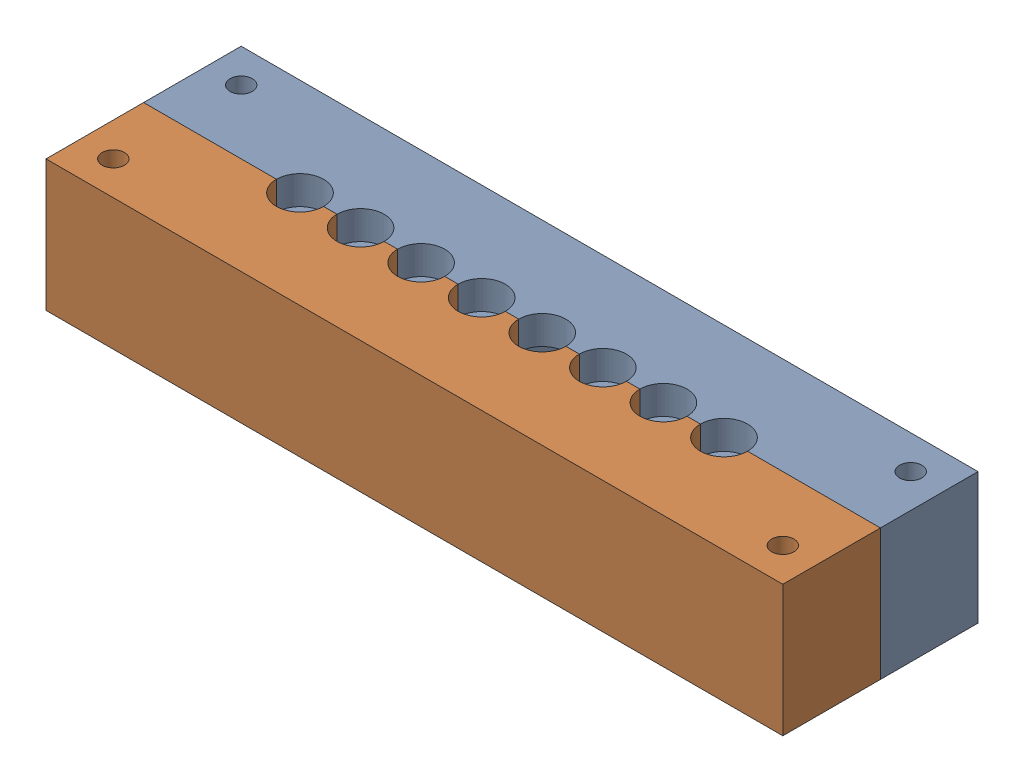
SolidWorks assembly board and upper, configuration Default. Lengths in mm.
Overall size (109.48 20.46 29).
15 component instances, 4 part files, 3 mates.
Components (placement in the parent):
- Photodiode_upper_v3-1: Photodiode_upper_v3 [Default] at (68.222 41.734 71.6201) size (109.48 19.5 29)
- Photodiode_Board-3: Photodiode_Board [Default] at (-11.918 65.909 111.5201) x (1 0 0) z (0 1 0) size (109.48 29 0)
  - Photodiode_Board_BOARD-1: Photodiode_Board_BOARD [Default] at origin (suppressed, hidden)
  - FP-PEC06SBBN-MFG_CMP-25680-000045-1-1: FP-PEC06SBBN-MFG_CMP-25680-000045-1 [Default] at (46.02 26.67 0.4115) (suppressed, hidden)
  - FP-PEC06SBBN-MFG_CMP-25680-000045-1-2: FP-PEC06SBBN-MFG_CMP-25680-000045-1 [Default] at (114.26 26.67 0.4115) (suppressed, hidden)
  - FP-PEC06SBBN-MFG_CMP-25680-000045-1-3: FP-PEC06SBBN-MFG_CMP-25680-000045-1 [Default] at (46.02 53.13 0.4115) x (-1 0 0) z (0 0 1) (suppressed, hidden)
  - FP-PEC06SBBN-MFG_CMP-25680-000045-1-4: FP-PEC06SBBN-MFG_CMP-25680-000045-1 [Default] at (114.26 53.13 0.4115) x (-1 0 0) z (0 0 1) (suppressed, hidden)
  - FP-6_550-5329_01-4-MFG_CMP-02531-000009-1-1: FP-6_550-5329_01-4-MFG_CMP-02531-000009-1 [Default] at (48.64 40.3 0.0102) x (-1 0 0) z (0 0 -1) (suppressed, hidden)
  - FP-6_550-5329_01-4-MFG_CMP-02531-000009-1-2: FP-6_550-5329_01-4-MFG_CMP-02531-000009-1 [Default] at (57.64 40.3 0.0102) x (-1 0 0) z (0 0 -1) (suppressed, hidden)
  - FP-6_550-5329_01-4-MFG_CMP-02531-000009-1-3: FP-6_550-5329_01-4-MFG_CMP-02531-000009-1 [Default] at (66.64 40.3 0.0102) x (-1 0 0) z (0 0 -1) (suppressed, hidden)
  - FP-6_550-5329_01-4-MFG_CMP-02531-000009-1-4: FP-6_550-5329_01-4-MFG_CMP-02531-000009-1 [Default] at (75.64 40.3 0.0102) x (-1 0 0) z (0 0 -1) (suppressed, hidden)
  - FP-6_550-5329_01-4-MFG_CMP-02531-000009-1-5: FP-6_550-5329_01-4-MFG_CMP-02531-000009-1 [Default] at (84.64 40.3 0.0102) x (-1 0 0) z (0 0 -1) (suppressed, hidden)
  - FP-6_550-5329_01-4-MFG_CMP-02531-000009-1-6: FP-6_550-5329_01-4-MFG_CMP-02531-000009-1 [Default] at (93.64 40.3 0.0102) x (-1 0 0) z (0 0 -1) (suppressed, hidden)
  - FP-6_550-5329_01-4-MFG_CMP-02531-000009-1-7: FP-6_550-5329_01-4-MFG_CMP-02531-000009-1 [Default] at (102.64 40.3 0.0102) x (-1 0 0) z (0 0 -1) (suppressed, hidden)
  - FP-6_550-5329_01-4-MFG_CMP-02531-000009-1-8: FP-6_550-5329_01-4-MFG_CMP-02531-000009-1 [Default] at (111.64 40.3 0.0102) x (-1 0 0) z (0 0 -1) (suppressed, hidden)
Mates (geometry in assembly coordinates):
- Distance2: distance = 2 mm anti-aligned: plane of Photodiode_Board-3/Photodiode_Board_BOARD-1 through (-11.918 65.909 111.5201) normal (0 -1 0); plane of Photodiode_upper_v3-1 through (68.222 63.909 86.1201) normal (0 1 0)
- Coincident1: coincident aligned: plane of Photodiode_upper_v3-1 through (68.222 41.734 86.1201) normal (0 0 1); plane of Photodiode_Board-3/Photodiode_Board_BOARD-1 through (122.962 66.3205 86.1201) normal (0 0 1)
- Coincident2: coincident aligned: plane of Photodiode_upper_v3-1 through (13.482 41.734 86.1201) normal (-1 0 0); plane of Photodiode_Board-3/Photodiode_Board_BOARD-1 through (13.482 66.3205 86.1201) normal (-1 0 0)
